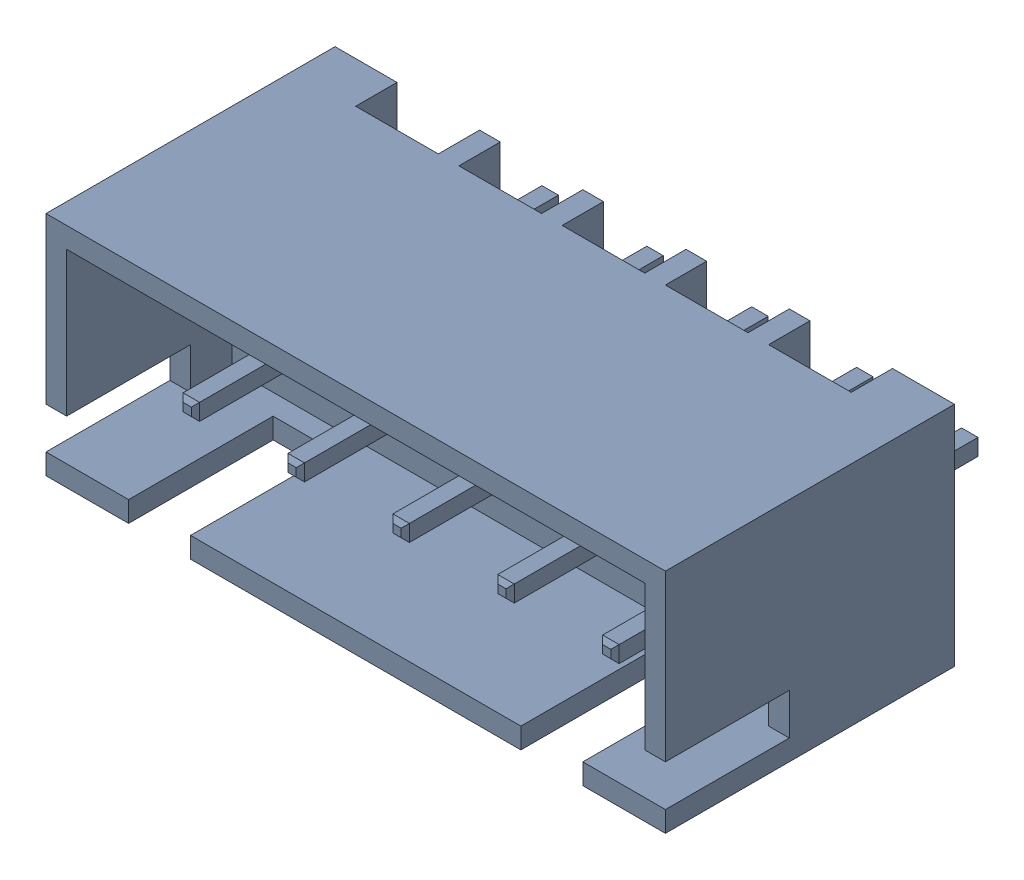
SolidWorks assembly motor_connector, configuration Default. Lengths in mm.
Overall size (15 5.5 9.89).
6 component instances, 2 part files, 0 mates.
Components (placement in the parent):
- motor_connector_1-1: motor_connector_1 [Default] at origin size (15 5.5 7)
- conn_lead_1-1: conn_lead_1 [Default] at origin size (0.4 0.4 8.89)
- conn_lead_1-2: conn_lead_1 [Default] at (-2.54 0 0) size (0.4 0.4 8.89)
- conn_lead_1-3: conn_lead_1 [Default] at (-5.08 0 0) size (0.4 0.4 8.89)
- conn_lead_1-4: conn_lead_1 [Default] at (-7.62 0 0) size (0.4 0.4 8.89)
- conn_lead_1-5: conn_lead_1 [Default] at (-10.16 0 0) size (0.4 0.4 8.89)
